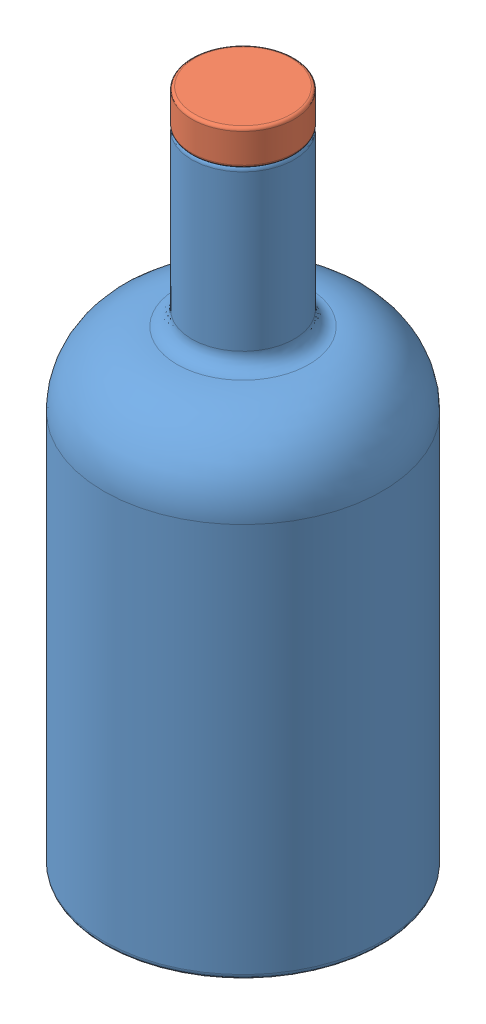
SolidWorks assembly Assem1, configuration Default. Lengths in mm.
Overall size (95 231 95).
2 component instances, 2 part files, 2 mates.
Components (placement in the parent):
- Bottle_body-1: Bottle_body [Default] at (-14.3336 -120.7793 14.887) size (95 220 95)
- Stopper-1: Stopper [Default] at (-14.3336 98.2207 14.887) size (35 32 35)
Mates (geometry in assembly coordinates):
- Concentric1: concentric: circle of Bottle_body-1; cylinder of Stopper-1 through (-14.3336 78.2207 14.887) axis (0 1 0) radius 10
- Coincident2: coincident aligned: plane of Bottle_body-1 through (-4.8336 99.2207 14.887) normal (0 1 0); circle of Stopper-1
